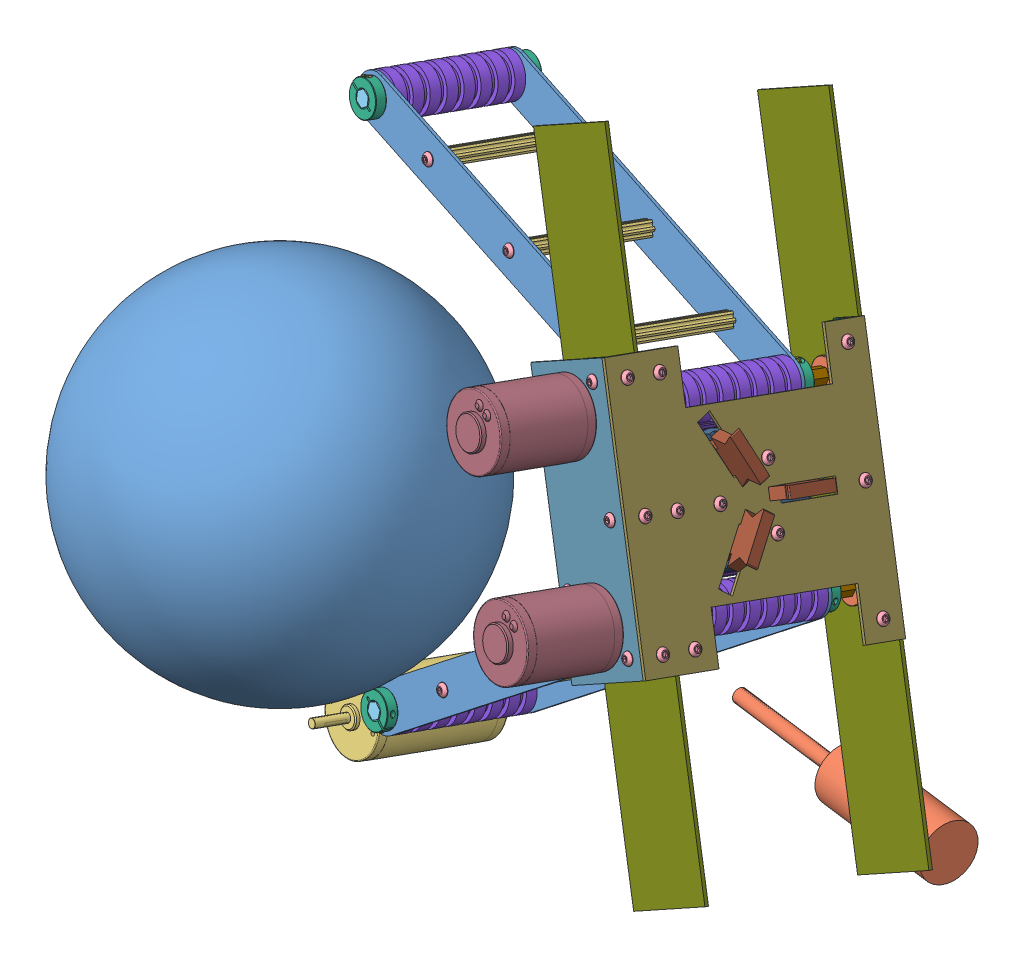
SolidWorks assembly 1504_Deep_Space_Intake_Prototype_21_concept-drive-arms_1, configuration Default. Lengths in mm.
Overall size (653.17 732.35 571.96).
130 component instances, 21 part files, 7 mates.
Components (placement in the parent):
- Arm_Assembly-1: Arm_Assembly [Default] at (-220.9143 54.1354 438.3222) x (0.535933 0.83696 -0.110787) z (-0.827046 0.494101 -0.268067) size (386.7 241.43 173.84)
  - Arms_Top_Bottom_Plate-1: Arms_Top_Bottom_Plate [Default] at (-277.9606 169.7769 222.1703) x (-0.345233 0 -0.938517) z (0 -1 0) size (38.57 397.35 3.17)
  - 1_2_Hex_Bore_Flange_Bearing-1: 1_2_Hex_Bore_Flange_Bearing [Default] at (58.7558 163.3736 98.3094) x (0.284409 0 0.958703) z (0 1 0) size (31.12 31.12 7.93)
  - 1_2_Hex_Bore_Flange_Bearing-2: 1_2_Hex_Bore_Flange_Bearing [Default] at (-277.9606 163.3736 222.1703) x (-0.84433 0 -0.535824) z (0 1 0) size (31.12 31.12 7.93)
  - 1_2_Hex_Bore_Flange_Bearing-3: 1_2_Hex_Bore_Flange_Bearing [Default] at (-277.9606 49.4043 222.1703) x (0.84433 0 0.535824) z (0 -1 0) size (31.12 31.12 7.93)
  - 1_2_Hex_Bore_Flange_Bearing-4: 1_2_Hex_Bore_Flange_Bearing [Default] at (58.7558 49.4043 98.3094) x (-0.284409 0 -0.958703) z (0 -1 0) size (31.12 31.12 7.93)
  - Arms_Top_Bottom_Plate-2: Arms_Top_Bottom_Plate [Default] at (-277.9606 43.0009 222.1703) x (0.345233 0 0.938517) z (0 1 0) size (38.57 397.35 3.17)
  - 1_2_5__Churro_Tube-1: 1_2_5__Churro_Tube [Default] at (-209.5369 98.8759 197.0007) x (-0.345233 0 -0.938517) z (0 1 0) size (14.66 12.7 120.43)
  - 1_2_5__Churro_Tube-2: 1_2_5__Churro_Tube [Default] at (-109.6024 98.8759 160.2399) x (-0.345233 0 -0.938517) z (0 1 0) size (14.66 12.7 120.43)
  - 1_2_5__Churro_Tube-3: 1_2_5__Churro_Tube [Default] at (-9.6679 98.8759 123.479) x (-0.345233 0 -0.938517) z (0 1 0) size (14.66 12.7 120.43)
  - 1_4-20_1_2_Button_Cap-1: 1_4-20_1_2_Button_Cap [Default] at (-9.6679 173.1297 123.479) x (-0.345233 0 -0.938517) z (0 1 0) size (11.17 11.22 17.01)
  - 1_4-20_1_2_Button_Cap-2: 1_4-20_1_2_Button_Cap [Default] at (-109.6024 173.1297 160.2399) x (-0.345233 0 -0.938517) z (0 1 0) size (11.17 11.22 17.01)
  - 1_4-20_1_2_Button_Cap-3: 1_4-20_1_2_Button_Cap [Default] at (-209.5369 173.1297 197.0007) x (-0.345233 0 -0.938517) z (0 1 0) size (11.17 11.22 17.01)
  - 1_4-20_1_2_Button_Cap-4: 1_4-20_1_2_Button_Cap [Default] at (-9.6679 39.6481 123.479) x (-0.345233 0 -0.938517) z (0 -1 0) size (11.17 11.22 17.01)
  - 1_4-20_1_2_Button_Cap-5: 1_4-20_1_2_Button_Cap [Default] at (-109.6024 39.6481 160.2399) x (-0.345233 0 -0.938517) z (0 -1 0) size (11.17 11.22 17.01)
  - 1_4-20_1_2_Button_Cap-6: 1_4-20_1_2_Button_Cap [Default] at (-209.5369 39.6481 197.0007) x (-0.345233 0 -0.938517) z (0 -1 0) size (11.17 11.22 17.01)
  - 0.5_Hex_Shaft_Idle-1: 0.5_Hex_Shaft_Idle [Default] at (-271.2056 40.7057 219.3585) x (-0.384298 0 -0.923209) z (0.923209 0 -0.384298) size (13.49 146 14.63)
  - 1_2_Hex_Shaft_Collar-1: 1_2_Hex_Shaft_Collar [Default] at (127.7816 408.0678 12.6986) size (42.94 10.19 42.95)
    - am-1238 Clamp Only-1: am-1238 Clamp Only [Default] at (-405.7309 -236.7669 209.4653) x (0.868523 0 -0.495649) z (0.495649 0 0.868523) size (31.47 10.19 31.5)
    - am-1238 Screw Only_91251A194-1: am-1238 Screw Only_91251A194 [Default] at (-392.5372 -232.0044 210.8557) x (0.868523 0 -0.495649) z (0.495649 0 0.868523) size (6.86 6.86 17.11)
  - 1_2_Hex_Shaft_Collar_1-1: 1_2_Hex_Shaft_Collar_1 [Default] at (75.9024 412.9384 -146.8237) size (32.06 10.19 32.03)
    - am-1238 Clamp Only-1: am-1238 Clamp Only [Default] at (-353.863 -379.4625 368.9941) x (0.017972 0 -0.999838) z (0.999838 0 0.017972) size (31.47 10.19 31.5)
    - am-1238 Screw Only_91251A194-1: am-1238 Screw Only_91251A194 [Default] at (-345.9237 -374.7 358.3651) x (0.017972 0 -0.999838) z (0.999838 0 0.017972) size (6.86 6.86 17.11)
  - Belt_Hub-1: Belt_Hub [Default] at (-277.9606 48.8891 222.1703) x (-0.384298 0 -0.923209) z (0 1 0) size (38.57 38.57 113.97)
  - 0.5_Hex_Shaft_Drive-1: 0.5_Hex_Shaft_Drive [Default] at (51.8162 4.5177 95.9906) x (-0.316916 0 0.948454) z (-0.948454 0 -0.316916) size (13.49 241.43 14.63)
  - Belt_Hub-2: Belt_Hub [Default] at (58.7558 52.1174 98.3094) x (-0.316916 0 0.948454) z (0 1 0) size (38.57 38.57 113.97)
  - 1_2_Hex_Shaft_Collar_2-1: 1_2_Hex_Shaft_Collar_2 [Default] at (-0.3501 536.1995 139.4112) size (39.15 10.19 39.13)
    - am-1238 Clamp Only-1: am-1238 Clamp Only [Default] at (59.1023 -364.8986 -41.1142) x (-0.284409 0 -0.958703) z (0.958703 0 -0.284409) size (31.47 10.19 31.5)
    - am-1238 Screw Only_91251A194-1: am-1238 Screw Only_91251A194 [Default] at (63.4663 -360.1361 -53.6427) x (-0.284409 0 -0.958703) z (0.958703 0 -0.284409) size (6.86 6.86 17.11)
  - 1_2_Hex_Shaft_Collar_3-1: 1_2_Hex_Shaft_Collar_3 [Default] at (56.7879 209.4764 105.0462) size (39.15 10.19 39.13)
    - am-1238 Clamp Only-1: am-1238 Clamp Only [Default] at (1.968 -177.5245 -6.7368) x (-0.284409 0 -0.958703) z (0.958703 0 -0.284409) size (31.47 10.19 31.5)
    - am-1238 Screw Only_91251A194-1: am-1238 Screw Only_91251A194 [Default] at (6.332 -172.762 -19.2653) x (-0.284409 0 -0.958703) z (0.958703 0 -0.284409) size (6.86 6.86 17.11)
- Assem42^1504_Deep_Space_Intake_Prototype_21_concept-drive-arms_1-1: Assem42^1504_Deep_Space_Intake_Prototype_21_concept-drive-arms_1 [Default] at (-311.8417 180.9149 296.0777) x (-0.467037 0.835919 -0.288299) z (0.867816 0.49586 0.031899) size (558.8 332.1 111.03) (virtual)
  - Air_Gripper_Assembly-1: Air_Gripper_Assembly [Default] x (0 0 -1) z (1 0 0) size (100.53 94.6 107)
    - Air_Gripper_Body-1: Air_Gripper_Body [Default] at (2.7288 -0.6305 1.3862) size (74.5 90.6 101.7)
    - Air_Gripper_Grip-1: Air_Gripper_Grip [Default] at (-58.2712 16.3695 30.831) x (1 0 0) z (0 0.866025 -0.5) size (49.23 44 20)
    - Air_Gripper_Grip-2: Air_Gripper_Grip [Default] at (-58.2712 -34.6305 1.3862) size (49.23 44 20)
    - Air_Gripper_Grip-3: Air_Gripper_Grip [Default] at (-58.2712 16.3695 -28.0587) x (1 0 0) z (0 0.866025 0.5) size (49.23 44 20)
  - Intake_Front_Plate-1: Intake_Front_Plate [Default] at (0 0 71.7712) size (230 230 3.17)
  - Intake_Top_Plate_Assembly-1: Intake_Top_Plate_Assembly [Default] x (0 0 1) z (-1 0 0) size (85 125.82 230)
    - Mini_Cim-1: Mini_Cim [Default] at (24.7712 115 -75) x (0 1 0) z (-1 0 0) size (125.82 64.01 64.01)
    - Intake_Top_Plate-1: Intake_Top_Plate [Default] at (29.2712 115 0) x (0 -1 0) z (0 0 1) size (3.17 85 230)
    - Mini_Cim-2: Mini_Cim [Default] at (24.7712 115 75) x (0 1 0) z (-1 0 0) size (125.82 64.01 64.01)
  - Intake_1_Angle-1: Intake_1_Angle [Default] at (-115 111.825 71.7712) x (1 0 0) z (0 0 -1) size (230 25.4 25.4)
  - Intake_1_Angle-2: Intake_1_Angle [Default] at (-115 83.25 71.7712) x (1 0 0) z (0 0 -1) size (230 25.4 25.4)
  - Intake_Top_Bearing_Plate_Assembly-1: Intake_Top_Bearing_Plate_Assembly [Default] x (0 1 0) z (-1 0 0) size (7.93 85 558.8)
    - 1_2_Hex_Bore_Flange_Bearing-1: 1_2_Hex_Bore_Flange_Bearing [Default] at (80.5297 -24.7712 75) x (0 0.715549 0.698562) z (1 0 0) size (31.12 31.12 7.93)
    - base-plate-long-1: base-plate-long [Default] at (83.25 -29.2712 0) size (3.17 85 558.8)
    - 1_2_Hex_Bore_Flange_Bearing-2: 1_2_Hex_Bore_Flange_Bearing [Default] at (80.5297 -24.7712 -75) x (0 -0.16623 0.986087) z (1 0 0) size (31.12 31.12 7.93)
  - Intake_1_Angle-3: Intake_1_Angle [Default] at (-115 -111.825 71.7712) x (1 0 0) z (0 1 0) size (230 25.4 25.4)
  - Intake_Top_Bearing_Plate_Assembly_1-1: Intake_Top_Bearing_Plate_Assembly_1 [Default] at (0 -175 0) x (0 -1 0) z (1 0 0) size (7.93 85 558.8)
    - 1_2_Hex_Bore_Flange_Bearing-1: 1_2_Hex_Bore_Flange_Bearing [Default] at (-65.8953 -24.7712 75) x (0 0.16623 0.986087) z (1 0 0) size (31.12 31.12 7.93)
    - base-plate-long-1: base-plate-long [Default] at (-63.175 -29.2712 0) size (3.17 85 558.8)
    - 1_2_Hex_Bore_Flange_Bearing-2: 1_2_Hex_Bore_Flange_Bearing [Default] at (-65.8953 -24.7712 -75) x (0 -0.715549 0.698562) z (1 0 0) size (31.12 31.12 7.93)
  - 1_2_7.8__Churro_Tube-1: 1_2_7.8__Churro_Tube [Default] at (48.5 18.699 -3.2288) x (1 0 0) z (0 1 0) size (14.66 12.7 198.25)
  - 1_2_7.8__Churro_Tube-2: 1_2_7.8__Churro_Tube [Default] at (-48.5 18.699 -3.2288) x (1 0 0) z (0 1 0) size (14.66 12.7 198.25)
  - 1_2_1__Churro_Tube-1: 1_2_1__Churro_Tube [Default] at (-48.5 216.949 -3.2288) x (1 0 0) z (0 1 0) size (14.66 12.7 25.4)
  - 1_2_1__Churro_Tube-2: 1_2_1__Churro_Tube [Default] at (48.5 216.949 -3.2288) x (1 0 0) z (0 1 0) size (14.66 12.7 25.4)
  - 1_2_Hex_Shaft_Collar_8-1: 1_2_Hex_Shaft_Collar_8 [Default] at (-17.2542 -136.0955 -57.1098) size (38.28 10.19 38.3)
    - am-1238 Clamp Only-1: am-1238 Clamp Only [Default] at (-57.7458 19.0635 81.881) x (0.968965 0 -0.247198) z (-0.247198 0 -0.968965) size (31.47 10.19 31.5)
    - am-1238 Screw Only_91251A194-1: am-1238 Screw Only_91251A194 [Default] at (-49.2252 14.301 71.7122) x (0.968965 0 -0.247198) z (-0.247198 0 -0.968965) size (6.86 6.86 17.11)
  - 1_2_Hex_Shaft_Collar_9-1: 1_2_Hex_Shaft_Collar_9 [Default] at (26.9774 -156.866 11.2972) size (36.27 10.19 36.29)
    - am-1238 Clamp Only-1: am-1238 Clamp Only [Default] at (48.0098 39.834 13.4762) x (-0.986087 0 0.16623) z (0.16623 0 0.986087) size (31.47 10.19 31.5)
    - am-1238 Screw Only_91251A194-1: am-1238 Screw Only_91251A194 [Default] at (38.6776 35.0715 22.9057) x (-0.986087 0 0.16623) z (0.16623 0 0.986087) size (6.86 6.86 17.11)
  - 1_2_Hex_Shaft_Collar_10-1: 1_2_Hex_Shaft_Collar_10 [Default] at (-23.7492 -9.7763 -31.088) size (36.27 10.19 36.29)
    - am-1238 Clamp Only-1: am-1238 Clamp Only [Default] at (98.7365 107.7583 55.8614) x (-0.986087 0 0.16623) z (0.16623 0 0.986087) size (31.47 10.19 31.5)
    - am-1238 Screw Only_91251A194-1: am-1238 Screw Only_91251A194 [Default] at (89.4042 102.9958 65.2909) x (-0.986087 0 0.16623) z (0.16623 0 0.986087) size (6.86 6.86 17.11)
  - 1_2_Hex_Shaft_Collar_11-1: 1_2_Hex_Shaft_Collar_11 [Default] at (-73.8312 105.2973 -77.358) size (44.52 10.19 44.52)
    - am-1238 Clamp Only-1: am-1238 Clamp Only [Default] at (-1.1779 -7.3153 102.1199) x (-0.698562 0 -0.715549) z (-0.715549 0 0.698562) size (31.47 10.19 31.5)
    - am-1238 Screw Only_91251A194-1: am-1238 Screw Only_91251A194 [Default] at (-14.2447 -12.0778 99.8253) x (-0.698562 0 -0.715549) z (-0.715549 0 0.698562) size (6.86 6.86 17.11)
  - 1_4-20_1_2_Button_Cap-1: 1_4-20_1_2_Button_Cap [Default] at (48.5 118.3528 -3.2288) x (1 0 0) z (0 1 0) size (11.17 11.22 17.01)
  - 1_4-20_1_2_Button_Cap-2: 1_4-20_1_2_Button_Cap [Default] at (-48.5 118.3528 -3.2288) x (1 0 0) z (0 1 0) size (11.17 11.22 17.01)
  - 1_4-20_1_2_Button_Cap-3: 1_4-20_1_2_Button_Cap [Default] at (98.571 118.3528 57.4832) x (1 0 0) z (0 1 0) size (11.17 11.22 17.01)
  - 1_4-20_1_2_Button_Cap-4: 1_4-20_1_2_Button_Cap [Default] at (0 118.3528 57.4832) x (1 0 0) z (0 1 0) size (11.17 11.22 17.01)
  - 1_4-20_1_2_Button_Cap-5: 1_4-20_1_2_Button_Cap [Default] at (-98.571 118.3528 57.4832) x (1 0 0) z (0 1 0) size (11.17 11.22 17.01)
  - 1_4-20_1_2_Button_Cap-6: 1_4-20_1_2_Button_Cap [Default] at (48.5 -118.3528 -3.2288) x (1 0 0) z (0 -1 0) size (11.17 11.22 17.01)
  - 1_4-20_1_2_Button_Cap-7: 1_4-20_1_2_Button_Cap [Default] at (-48.5 -118.3528 -3.2288) x (1 0 0) z (0 -1 0) size (11.17 11.22 17.01)
  - 1_4-20_1_2_Button_Cap-8: 1_4-20_1_2_Button_Cap [Default] at (0 31 78.299) size (11.17 11.22 17.01)
  - 1_4-20_1_2_Button_Cap-9: 1_4-20_1_2_Button_Cap [Default] at (26.8464 -15.5007 78.299) size (11.17 11.22 17.01)
  - 1_4-20_1_2_Button_Cap-10: 1_4-20_1_2_Button_Cap [Default] at (-26.8476 -15.5 78.299) size (11.17 11.22 17.01)
  - 1_4-20_1_2_Button_Cap-11: 1_4-20_1_2_Button_Cap [Default] at (-98.571 68.962 78.299) size (11.17 11.22 17.01)
  - 1_4-20_1_2_Button_Cap-12: 1_4-20_1_2_Button_Cap [Default] at (0 68.962 78.299) size (11.17 11.22 17.01)
  - 1_4-20_1_2_Button_Cap-13: 1_4-20_1_2_Button_Cap [Default] at (98.571 68.962 78.299) size (11.17 11.22 17.01)
  - 1_4-20_1_2_Button_Cap-14: 1_4-20_1_2_Button_Cap [Default] at (-98.571 97.537 78.299) size (11.17 11.22 17.01)
  - 1_4-20_1_2_Button_Cap-15: 1_4-20_1_2_Button_Cap [Default] at (0 97.537 78.299) size (11.17 11.22 17.01)
  - 1_4-20_1_2_Button_Cap-16: 1_4-20_1_2_Button_Cap [Default] at (98.571 97.537 78.299) size (11.17 11.22 17.01)
  - 1_4-20_1_2_Button_Cap-17: 1_4-20_1_2_Button_Cap [Default] at (-98.571 -97.537 78.299) size (11.17 11.22 17.01)
  - 1_4-20_1_2_Button_Cap-18: 1_4-20_1_2_Button_Cap [Default] at (0 -97.537 78.299) size (11.17 11.22 17.01)
  - 1_4-20_1_2_Button_Cap-19: 1_4-20_1_2_Button_Cap [Default] at (98.571 -97.537 78.299) size (11.17 11.22 17.01)
  - 1_4-20_1_2_Button_Cap-20: 1_4-20_1_2_Button_Cap [Default] at (0 76.7222 57.4837) x (1 0 0) z (0 -1 0) size (11.17 11.22 17.01)
  - 1_4-20_1_2_Button_Cap-21: 1_4-20_1_2_Button_Cap [Default] at (99.6667 76.7222 57.4837) x (1 0 0) z (0 -1 0) size (11.17 11.22 17.01)
  - 1_4-20_1_2_Button_Cap-22: 1_4-20_1_2_Button_Cap [Default] at (-99.6667 76.7222 57.4837) x (1 0 0) z (0 -1 0) size (11.17 11.22 17.01)
  - 1_4-20_1_2_Button_Cap-23: 1_4-20_1_2_Button_Cap [Default] at (98.571 -118.3528 57.4832) x (1 0 0) z (0 -1 0) size (11.17 11.22 17.01)
  - 1_4-20_1_2_Button_Cap-24: 1_4-20_1_2_Button_Cap [Default] at (0 -118.3528 57.4832) x (1 0 0) z (0 -1 0) size (11.17 11.22 17.01)
  - 1_4-20_1_2_Button_Cap-25: 1_4-20_1_2_Button_Cap [Default] at (-98.571 -118.3528 57.4832) x (1 0 0) z (0 -1 0) size (11.17 11.22 17.01)
- Arm_Assembly_1-1: Arm_Assembly_1 [Default] at (-299.5318 374.182 345.7007) x (-0.686076 0.668929 -0.286065) z (-0.70748 -0.705104 0.047964) size (349.83 241.43 256.87)
  - Arms_Top_Bottom_Plate-1: Arms_Top_Bottom_Plate [Default] at (254.6361 169.7769 301.2241) x (-0.565577 0 0.824696) z (0 -1 0) size (38.57 397.35 3.17)
  - 1_2_Hex_Bore_Flange_Bearing-1: 1_2_Hex_Bore_Flange_Bearing [Default] at (-41.2442 163.3736 98.3094) x (-0.99727 0 -0.073836) z (0 1 0) size (31.12 31.12 7.93)
  - 1_2_Hex_Bore_Flange_Bearing-2: 1_2_Hex_Bore_Flange_Bearing [Default] at (254.6361 163.3736 301.2241) x (0.800289 0 -0.599615) z (0 1 0) size (31.12 31.12 7.93)
  - 1_2_Hex_Bore_Flange_Bearing-3: 1_2_Hex_Bore_Flange_Bearing [Default] at (254.6361 49.4043 301.2241) x (-0.800289 0 0.599615) z (0 -1 0) size (31.12 31.12 7.93)
  - 1_2_Hex_Bore_Flange_Bearing-4: 1_2_Hex_Bore_Flange_Bearing [Default] at (-41.2442 49.4043 98.3094) x (0.99727 0 0.073836) z (0 -1 0) size (31.12 31.12 7.93)
  - Arms_Top_Bottom_Plate-2: Arms_Top_Bottom_Plate [Default] at (254.6361 43.0009 301.2241) x (0.565577 0 -0.824696) z (0 1 0) size (38.57 397.35 3.17)
  - 1_2_5__Churro_Tube-1: 1_2_5__Churro_Tube [Default] at (194.5106 98.8759 259.9901) x (-0.565577 0 0.824696) z (0 1 0) size (14.66 12.7 120.43)
  - 1_2_5__Churro_Tube-2: 1_2_5__Churro_Tube [Default] at (106.696 98.8759 199.7668) x (-0.565577 0 0.824696) z (0 1 0) size (14.66 12.7 120.43)
  - 1_2_5__Churro_Tube-3: 1_2_5__Churro_Tube [Default] at (18.8813 98.8759 139.5435) x (-0.565577 0 0.824696) z (0 1 0) size (14.66 12.7 120.43)
  - 1_4-20_1_2_Button_Cap-1: 1_4-20_1_2_Button_Cap [Default] at (18.8813 173.1297 139.5435) x (-0.565577 0 0.824696) z (0 1 0) size (11.17 11.22 17.01)
  - 1_4-20_1_2_Button_Cap-2: 1_4-20_1_2_Button_Cap [Default] at (106.696 173.1297 199.7668) x (-0.565577 0 0.824696) z (0 1 0) size (11.17 11.22 17.01)
  - 1_4-20_1_2_Button_Cap-3: 1_4-20_1_2_Button_Cap [Default] at (194.5106 173.1297 259.9901) x (-0.565577 0 0.824696) z (0 1 0) size (11.17 11.22 17.01)
  - 1_4-20_1_2_Button_Cap-4: 1_4-20_1_2_Button_Cap [Default] at (18.8813 39.6481 139.5435) x (-0.565577 0 0.824696) z (0 -1 0) size (11.17 11.22 17.01)
  - 1_4-20_1_2_Button_Cap-5: 1_4-20_1_2_Button_Cap [Default] at (106.696 39.6481 199.7668) x (-0.565577 0 0.824696) z (0 -1 0) size (11.17 11.22 17.01)
  - 1_4-20_1_2_Button_Cap-6: 1_4-20_1_2_Button_Cap [Default] at (194.5106 39.6481 259.9901) x (-0.565577 0 0.824696) z (0 -1 0) size (11.17 11.22 17.01)
  - 0.5_Hex_Shaft_Idle-1: 0.5_Hex_Shaft_Idle [Default] at (254.8713 40.7057 308.5372) x (0.999483 0 -0.032149) z (0.032149 0 0.999483) size (13.49 146 14.63)
  - 1_2_Hex_Shaft_Collar_4-1: 1_2_Hex_Shaft_Collar_4 [Default] at (127.7816 408.0678 12.6986) size (36.01 10.19 35.99)
    - am-1238 Clamp Only-1: am-1238 Clamp Only [Default] at (126.8565 -236.7669 288.5384) x (0.155654 0 0.987812) z (-0.987812 0 0.155654) size (31.47 10.19 31.5)
    - am-1238 Screw Only_91251A194-1: am-1238 Screw Only_91251A194 [Default] at (120.8803 -232.0044 300.3828) x (0.155654 0 0.987812) z (-0.987812 0 0.155654) size (6.86 6.86 17.11)
  - 1_2_Hex_Shaft_Collar_5-1: 1_2_Hex_Shaft_Collar_5 [Default] at (75.9024 412.9384 -146.8237) size (40.91 10.19 40.93)
    - am-1238 Clamp Only-1: am-1238 Clamp Only [Default] at (178.7337 -379.4625 448.0479) x (0.928566 0 0.371168) z (-0.371168 0 0.928566) size (31.47 10.19 31.5)
    - am-1238 Screw Only_91251A194-1: am-1238 Screw Only_91251A194 [Default] at (185.8588 -374.7 459.2389) x (0.928566 0 0.371168) z (-0.371168 0 0.928566) size (6.86 6.86 17.11)
  - Belt_Hub-1: Belt_Hub [Default] at (254.6361 48.8891 301.2241) x (0.999483 0 -0.032149) z (0 1 0) size (38.57 38.57 113.97)
  - 0.5_Hex_Shaft_Drive-1: 0.5_Hex_Shaft_Drive [Default] at (-36.6163 4.5177 92.642) x (-0.774565 0 -0.632494) z (0.632494 0 -0.774565) size (13.49 241.43 14.63)
  - Belt_Hub-2: Belt_Hub [Default] at (-41.2442 52.1174 98.3094) x (-0.774565 0 -0.632494) z (0 1 0) size (38.57 38.57 113.97)
  - 1_2_Hex_Shaft_Collar_6-1: 1_2_Hex_Shaft_Collar_6 [Default] at (-0.3501 536.1995 139.4112) size (33.71 10.19 33.73)
    - am-1238 Clamp Only-1: am-1238 Clamp Only [Default] at (-40.8811 -364.8986 -41.1008) x (0.99727 0 0.073836) z (-0.073836 0 0.99727) size (31.47 10.19 31.5)
    - am-1238 Screw Only_91251A194-1: am-1238 Screw Only_91251A194 [Default] at (-30.7126 -360.1361 -32.5798) x (0.99727 0 0.073836) z (-0.073836 0 0.99727) size (6.86 6.86 17.11)
  - 1_2_Hex_Shaft_Collar_7-1: 1_2_Hex_Shaft_Collar_7 [Default] at (56.7879 209.4764 105.0462) size (33.71 10.19 33.73)
    - am-1238 Clamp Only-1: am-1238 Clamp Only [Default] at (-98.032 -177.5245 -6.7368) x (0.99727 0 0.073836) z (-0.073836 0 0.99727) size (31.47 10.19 31.5)
    - am-1238 Screw Only_91251A194-1: am-1238 Screw Only_91251A194 [Default] at (-87.8635 -172.762 1.7842) x (0.99727 0 0.073836) z (-0.073836 0 0.99727) size (6.86 6.86 17.11)
- cargo ball-1: cargo ball [Default] at (-555.6089 1.5255 463.6699) size (330.2 330.2 330.2)
- cylinder-1: cylinder [Default] at (-227.4448 -53.3233 221.9194) x (0.985509 0.040497 0.164716) z (-0.15942 -0.11054 0.981003) size (254 50.8 50.8)
- cim2.5motor-1: cim2.5motor [Default] at (-628.5273 -228.8702 354.4548) x (0.985298 0.020394 0.169621) z (-0.169621 0.235292 0.957009) size (64.01 64.01 154.93)
Mates (geometry in assembly coordinates):
- Concentric1: concentric anti-aligned: cylinder of Arm_Assembly_1-1/0.5_Hex_Shaft_Drive-1 through (-341.2619 277.9329 364.8933) axis (0.169621 -0.235292 -0.957009) radius 4; cylinder of Assem42^1504_Deep_Space_Intake_Prototype_21_concept-drive-arms_1-1/Intake_Top_Plate_Assembly-1/Mini_Cim-1 through (-344.879 282.9505 385.3015) axis (-0.169621 0.235292 0.957009) radius 4
- Coincident1: coincident anti-aligned: plane of Assem42^1504_Deep_Space_Intake_Prototype_21_concept-drive-arms_1-1/Intake_Top_Plate_Assembly-1/Mini_Cim-1 through (-346.0687 285.353 380.3203) normal (0.169621 -0.235292 -0.957009); plane of Arm_Assembly_1-1/0.5_Hex_Shaft_Drive-1 through (-344.2005 282.0093 381.4734) normal (-0.169621 0.235292 0.957009)
- Concentric2: concentric anti-aligned: cylinder of Arm_Assembly-1/0.5_Hex_Shaft_Drive-1 through (-271.2063 152.5451 408.1381) axis (0.169621 -0.235292 -0.957009) radius 4; cylinder of Assem42^1504_Deep_Space_Intake_Prototype_21_concept-drive-arms_1-1/Intake_Top_Plate_Assembly-1/Mini_Cim-2 through (-274.8234 157.5627 428.5463) axis (-0.169621 0.235292 0.957009) radius 4
- Coincident2: coincident anti-aligned: plane of Arm_Assembly-1/0.5_Hex_Shaft_Drive-1 through (-274.1449 156.6215 424.7182) normal (-0.169621 0.235292 0.957009); plane of Assem42^1504_Deep_Space_Intake_Prototype_21_concept-drive-arms_1-1/Intake_Top_Plate_Assembly-1/Mini_Cim-2 through (-276.0131 159.9652 423.565) normal (0.169621 -0.235292 -0.957009)
- Tangent1: tangent anti-aligned: plane of Assem42^1504_Deep_Space_Intake_Prototype_21_concept-drive-arms_1-1/Intake_Top_Bearing_Plate_Assembly_1-1/base-plate-long-1 through (-266.9332 168.3708 186.9553) normal (0.169621 -0.235292 -0.957009); cylinder of cylinder-1 through (-361.0317 -58.8127 199.592) axis (-0.985509 -0.040497 -0.164716) radius 25.4
- Parallel1: parallel: plane of Arm_Assembly-1/Arms_Top_Bottom_Plate-2 through (-404.8856 31.4594 366.3575) normal (-0.169621 0.235292 0.957009); plane of cim2.5motor-1 through (-594.4925 -117.4584 353.001) normal (-0.169621 0.235292 0.957009)
- Lock1: lock: unknown of Arm_Assembly-1/1_2_Hex_Shaft_Collar_1-1/am-1238 Clamp Only-1; unknown of cim2.5motor-1
